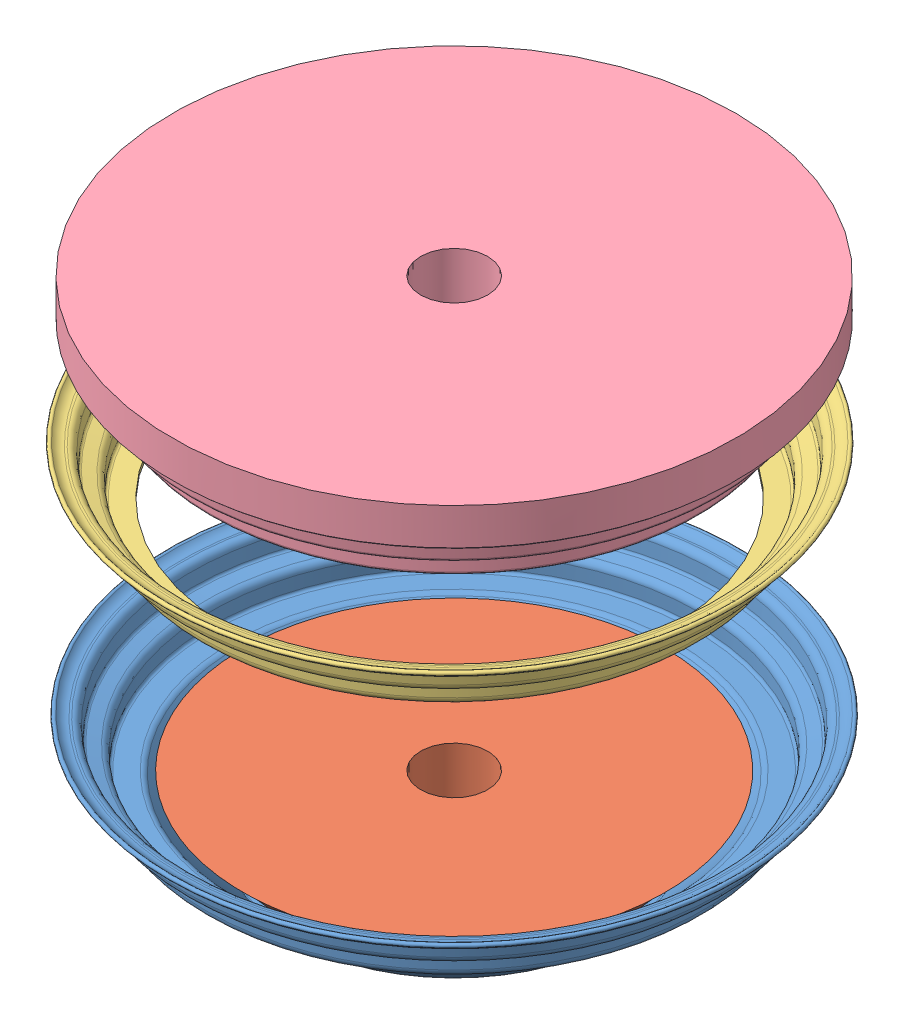
SolidWorks assembly BuckSpunAll, configuration Default. Lengths in mm.
Overall size (444.32 403.46 440.9).
5 component instances, 4 part files, 2 mates.
Components (placement in the parent):
- spun wheel125-1-1: spun wheel125-1 [Default] at (1207.9297 48.5736 -99.4752) size (432.05 86.66 432.05)
- buck extension^BuckSpunAll-1: buck extension^BuckSpunAll [Default] at (1207.9297 2708.4438 -99.4752) x (0.950968 0 0.309288) z (-0.309288 0 0.950968) size (319.83 45.06 319.83) (virtual)
- buck-spun-1: buck-spun [Default] at (1195.6609 216.6192 -108.3255) size (441.6 190.41 438.18)
  - spun wheel125-2-1: spun wheel125-2 [Default] at origin size (432.05 41.65 432.05)
  - buck Main^buck-spun-1: buck Main^buck-spun [Default] at (12.2688 90.743 8.8503) size (426.62 65.71 426.62) (virtual)
Mates (geometry in assembly coordinates):
- Concentric1: concentric anti-aligned: cylinder of buck extension^BuckSpunAll-1 through (1207.9297 2708.4438 -99.4752) axis (0 1 0) radius 25.4; cylinder of buck-spun-1/buck Main^buck-spun-1 through (1207.9297 307.3621 -99.4752) axis (0 -1 0) radius 25.4036
- Concentric2: concentric aligned: cylinder of spun wheel125-1-1 through (1207.9297 289.4625 -99.4752) axis (0 1 0) radius 102; cylinder of buck extension^BuckSpunAll-1 through (1207.9297 2708.4438 -99.4752) axis (0 1 0) radius 25.4
